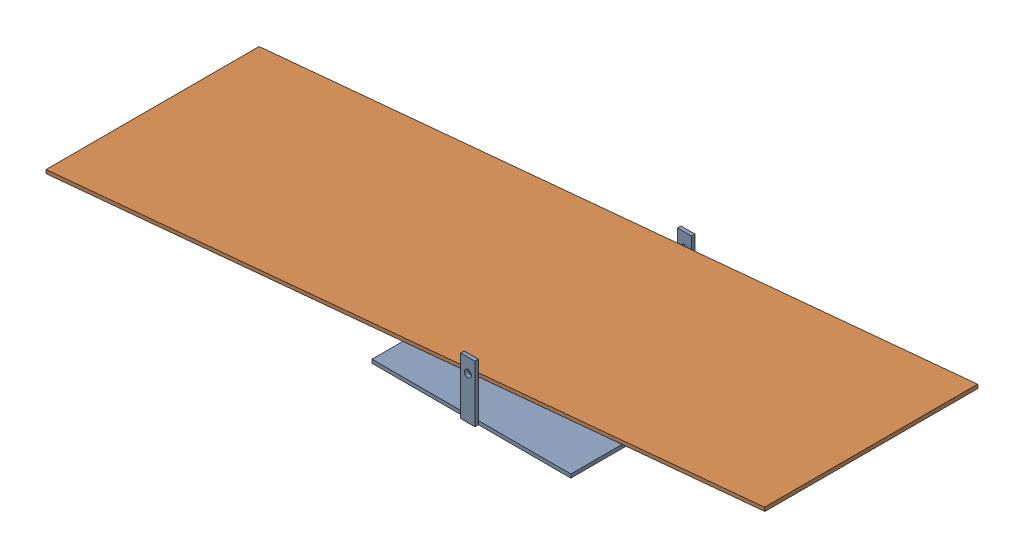
SolidWorks assembly PerfStageSeeSaw, configuration Default. Lengths in mm.
Overall size (1012.1 100.9 310).
2 component instances, 2 part files, 2 mates.
Components (placement in the parent):
- NSeeSawBase-1: NSeeSawBase [Default] at origin size (280 80 310)
- NSeeSawPlank-1: NSeeSawPlank [Default] at (-458.4312 1.8123 0) x (0.995701 0.092623 0) z (0 0 1) size (1016 5 300)
Mates (geometry in assembly coordinates):
- Coincident2: coincident: line of NSeeSawBase-1 through (140 60 -300) axis (0 0 1); cylinder of NSeeSawPlank-1 through (138.7509 59.9515 -300) axis (0 0 1) radius 1.25
- Coincident3: coincident anti-aligned: plane of NSeeSawBase-1 through (0 0 0) normal (0 0 -1); plane of NSeeSawPlank-1 through (-458.8943 6.7908 0) normal (0 0 1)
